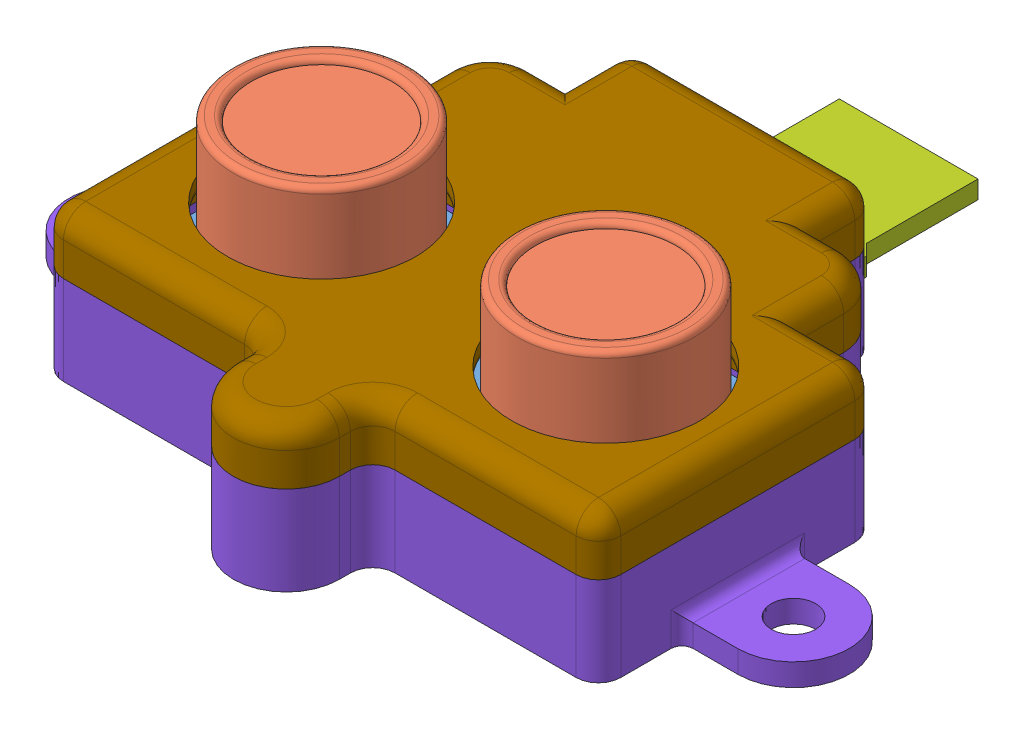
SolidWorks assembly SMU_assem, configuration Default. Lengths in mm.
Overall size (70 19.75 60.58).
18 component instances, 9 part files, 10 mates.
Components (placement in the parent):
- HC-SR04 Ping Sensor-2: HC-SR04 Ping Sensor [Default] at (16.8208 22.0579 40.5842) x (0 0 -1) z (0 1 0) size (25.18 45 18.07)
  - PCB-1: PCB [Default] at origin size (20.5 45 1.75)
  - Transducer-1: Transducer [Default] at (0 -13.16 13.25) x (1 0 0) z (0 -1 0) size (15.88 12 15.88)
  - Transducer-2: Transducer [Default] at (0 12.34 13.25) x (1 0 0) z (0 -1 0) size (15.88 12 15.88)
  - 3 Pin Header 90 Degree-1: 3 Pin Header 90 Degree [Default] at (8.4275 0 -1.25) x (-1 0 0) z (0 -1 0) size (8 7.82 10)
  - 14 Pin SMT-1: 14 Pin SMT [Default] at (-0.35 -18.5 -0.85) x (0 -1 0) z (1 0 0) size (6 1.6 8.8)
  - 14 Pin SMT-2: 14 Pin SMT [Default] at (0 -0.3826 -0.85) x (1 0 0) z (0 1 0) size (6 1.6 8.8)
  - 14 Pin SMT-3: 14 Pin SMT [Default] at (0 17.5274 -0.85) x (1 0 0) z (0 1 0) size (6 1.6 8.8)
  - Cap1 SMT-1: Cap1 SMT [Default] at (-1.755 7.4774 -0.9689) x (0 1 0) z (-1 0 0) size (4.5 1.84 1.75)
  - Cap1 SMT-2: Cap1 SMT [Default] at (6.835 7.4774 -0.9689) x (0 1 0) z (-1 0 0) size (4.5 1.84 1.75)
  - Cap1 SMT-3: Cap1 SMT [Default] at (-6.835 7.4774 -0.9689) x (0 1 0) z (-1 0 0) size (4.5 1.84 1.75)
  - Cap1 SMT-4: Cap1 SMT [Default] at (4.295 7.4774 -0.9689) x (0 1 0) z (-1 0 0) size (4.5 1.84 1.75)
  - Cap1 SMT-5: Cap1 SMT [Default] at (1.755 7.4774 -0.9689) x (0 1 0) z (-1 0 0) size (4.5 1.84 1.75)
  - Cap1 SMT-6: Cap1 SMT [Default] at (-4.295 7.4774 -0.9689) x (0 1 0) z (-1 0 0) size (4.5 1.84 1.75)
  - HC-SR04 Crystal-1: HC-SR04 Crystal [Default] at (-8.3 0 1.75) x (0 -1 0) z (0 0 1) size (10 3.5 2.7)
- SMU_pcb-1: SMU_pcb [Default] at (16.8208 18.3753 0.2567) x (0 0 1) z (-1 0 0) size (30.4 1.62 14.45)
- SMU_case_bottom-2: SMU_case_bottom [Default] at (16.8208 16.0579 14.0842) x (1 0 0) z (0 1 0) size (70 46.75 8)
- SMU_case_top-1: SMU_case_top [Default] at (16.8208 24.0579 14.0842) x (1 0 0) z (0 1 0) size (50 46.75 9)
Mates (geometry in assembly coordinates):
- Coincident1: coincident: plane of HC-SR04 Ping Sensor-2/PCB-1 through (16.8208 22.0579 40.5842) normal (-1 0 0); plane of SMU_pcb-1 through (16.8208 18.3753 0.2567) normal (-1 0 0)
- Coincident2: coincident: plane of HC-SR04 Ping Sensor-2/3 Pin Header 90 Degree-1 through (17.5008 18.3753 31.6542) normal (0 1 0); plane of SMU_pcb-1 through (16.8208 18.3753 0.2567) normal (0 -1 0)
- Coincident3: coincident: plane of HC-SR04 Ping Sensor-2/3 Pin Header 90 Degree-1 through (21.8208 19.5579 30.6567) normal (0 0 -1); plane of SMU_pcb-1 through (10.5978 19.9953 30.6567) normal (0 0 1)
- Coincident14: coincident: plane of HC-SR04 Ping Sensor-2/PCB-1 through (16.8208 22.0579 40.5842) normal (-1 0 0); plane of SMU_case_bottom-2 through (16.8208 16.0579 14.0842) normal (1 0 0)
- Concentric1: concentric: cylinder of HC-SR04 Ping Sensor-2/PCB-1 through (37.2708 19.0881 32.3842) axis (0 1 0) radius 1.05; cylinder of SMU_case_bottom-2 through (37.2708 20.0579 32.3842) axis (0 1 0) radius 1
- Coincident15: coincident: plane of HC-SR04 Ping Sensor-2/PCB-1 through (39.3208 22.0579 50.8342) normal (0 -1 0); plane of SMU_case_bottom-2 through (16.8208 22.0579 14.0842) normal (0 1 0)
- InPlace3: in place: plane of SMU_case_bottom-2 through (16.8208 24.0579 14.0842) normal (0 1 0); plane of ? through (0 24.0579 0) normal (0 1 0); moOrthogonalPlaneRef_w of SMU_case_bottom-2 through (16.8208 24.0579 14.0842) normal (0 1 0); plane of ? through (0 24.0579 0) normal (0 0 -1); plane of SMU_case_bottom-2 through (16.8208 24.0579 14.0842) normal (0 1 0); plane of ? through (0 24.0579 0) normal (1 0 0); plane of SMU_case_bottom-2 through (16.8208 24.0579 14.0842) normal (0 1 0); unknown of SMU_case_top-1
- Coincident16: coincident: plane of ?; plane of ?
- Coincident17: coincident: moOrthogonalPlaneRef_w of SMU_case_bottom-2 through (16.8208 24.0579 14.0842) normal (0 0 -1); plane of SMU_case_top-1 through (16.8208 24.0579 14.0842) normal (0 0 -1)
- Coincident18: coincident: moOrthogonalPlaneRef_w of SMU_case_bottom-2 through (16.8208 24.0579 14.0842) normal (-1 0 0); plane of SMU_case_top-1 through (16.8208 24.0579 14.0842) normal (1 0 0)
